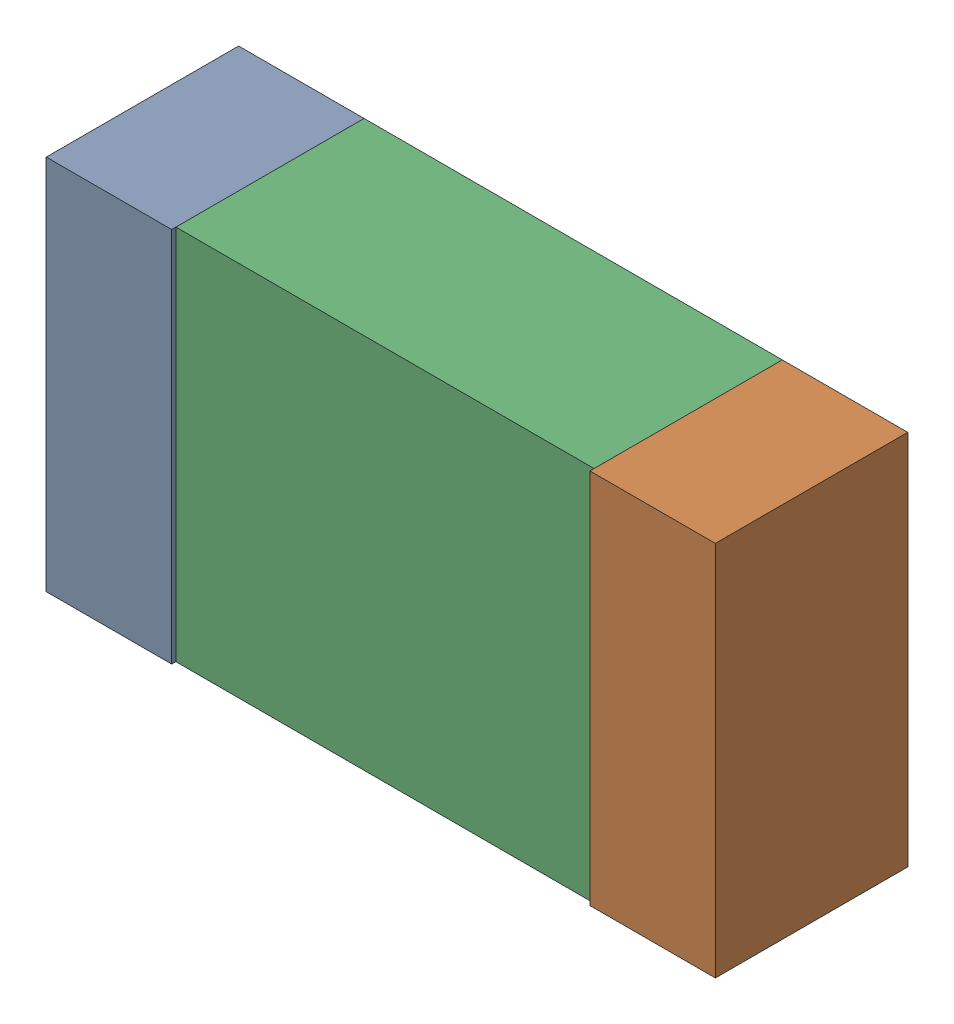
SolidWorks assembly C5, configuration Default. Lengths in mm.
Overall size (1.6 0.9 0.46).
6 component instances, 2 part files, 0 mates.
Components (placement in the parent):
- 870942080-1: 870942080 [Default] at (72.7044 5.4842 0) size (0.3 0.9 0.46)
  - Extruded_15-1: Extruded_15 [Default] at origin size (0.3 0.9 0.46)
- 870942080-2: 870942080 [Default] at (74.0044 5.4842 0) size (0.3 0.9 0.46)
  - Extruded_15-1: Extruded_15 [Default] at origin size (0.3 0.9 0.46)
- 870942240-1: 870942240 [Default] at (73.3544 5.4842 0) size (1 0.9 0.45)
  - Extruded_14-1: Extruded_14 [Default] at origin size (1 0.9 0.45)
